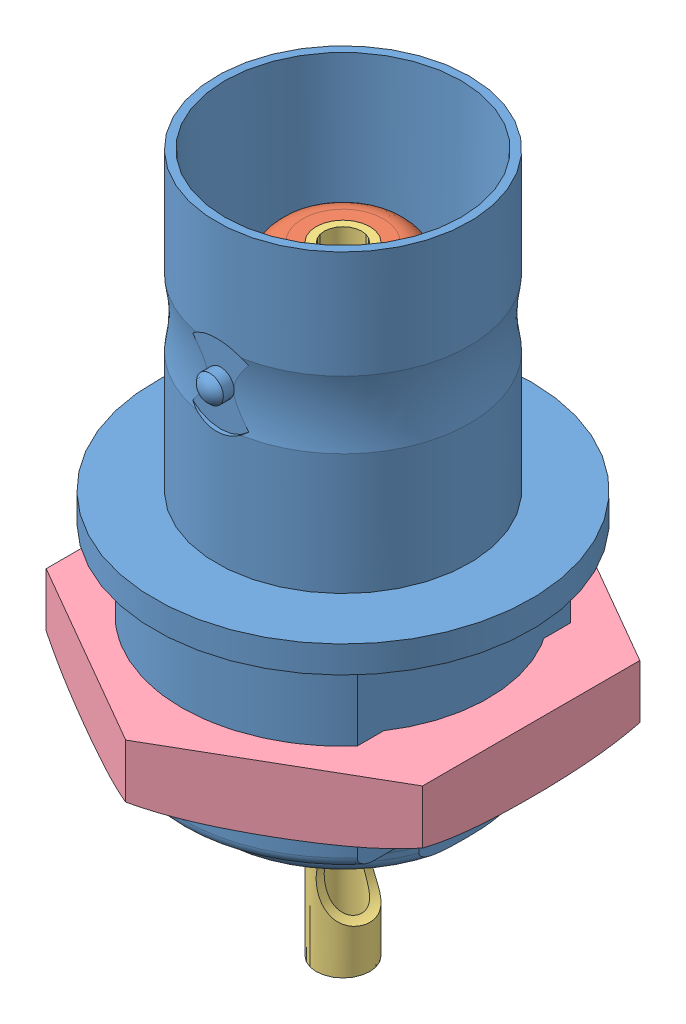
SolidWorks assembly BNC, configuration По умолчанию. Lengths in mm.
Overall size (21 26 20.21).
4 component instances, 4 part files, 8 mates.
Components (placement in the parent):
- BNC_Body-1: BNC_Body [По умолчанию] at origin size (14 20.16 14)
- BNC_Insulator-1: BNC_Insulator [По умолчанию] at origin size (8 18.5 8)
- BNC_Connector-1: BNC_Connector [По умолчанию] at (0 -6 0) size (2 23 2)
- M12-1: M12 [По умолчанию] at (0 5 0) x (0.5 0 0.866025) z (0.866025 0 -0.5) size (14 3.37 16.17)
Mates (geometry in assembly coordinates):
- Концентричный1: concentric aligned: cylinder of BNC_Insulator-1 through (0 0 0) axis (0 -1 0) radius 1; cylinder of BNC_Connector-1 through (0 -6 0) axis (0 -1 0) radius 1
- Совпадение1: coincident aligned: plane of BNC_Insulator-1 through (0 17 -1.5) normal (0 1 0); plane of BNC_Connector-1 through (0 17 -0.7) normal (0 1 0)
- Параллельность1: parallel aligned: plane of BNC_Body-1 through (4.5 0 -10) normal (1 0 0); plane of M12-1 through (7 2.5 -4.0415) normal (1 0 0)
- Расстояние1: distance = 3 mm anti-aligned: plane of M12-1 through (0 5 0) normal (0 1 0); plane of BNC_Body-1 through (0 8 -7) normal (0 -1 0)
- Совпадение3: coincident aligned: plane of BNC_Body-1 through (0 0 0) normal (0 0 1); plane of BNC_Connector-1 through (0 -6 0) normal (0 0 1)
- Совпадение4: coincident aligned: plane of BNC_Body-1 through (0 0 0) normal (0 0 1); plane of BNC_Insulator-1 through (0 0 0) normal (0 0 1)
- Совпадение5: coincident anti-aligned: plane of BNC_Body-1 through (0 8 -4) normal (0 1 0); plane of BNC_Insulator-1 through (0 8 -4) normal (0 -1 0)
- Концентричный3: concentric aligned: cone of BNC_Body-1 through (0 20 0) axis (0 -1 0); cylinder of BNC_Insulator-1 through (0 0 0) axis (0 -1 0) radius 3
